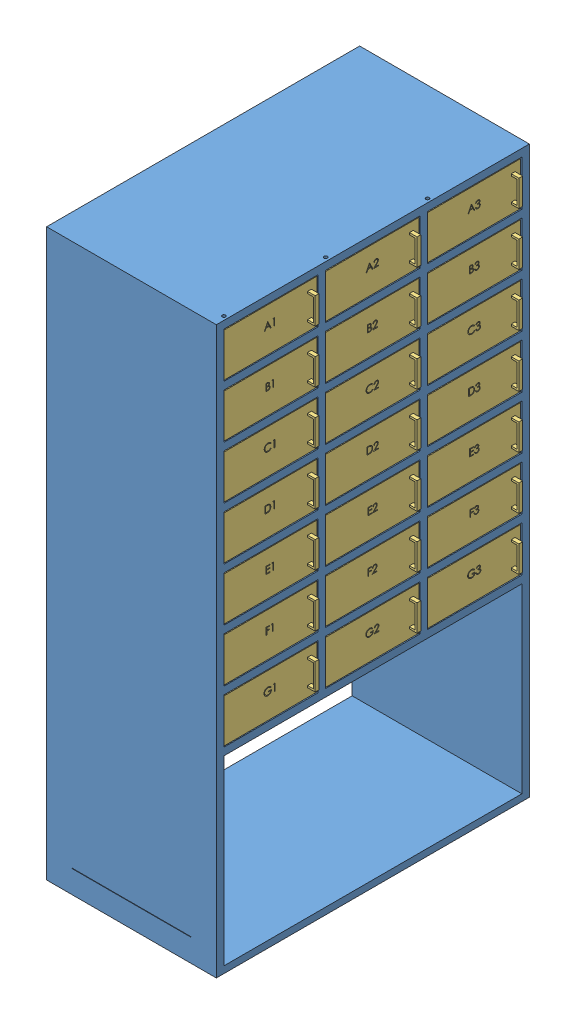
SolidWorks assembly new final assembly, configuration Default. Lengths in mm.
Overall size (470.03 1500 830).
64 component instances, 3 part files, 7 mates.
Components (placement in the parent):
- storage_frame-1: storage_frame [Default] at (-177.8301 428.9842 1746.1923) x (0 0 -1) z (1 0 0) size (830 1500 450)
- pivot mentese-1: pivot mentese [Varsayılan] at (37.1699 1388.9842 1996.1923) size (13 32 13)
- pivot mentese-2: pivot mentese [Varsayılan] at (37.1699 1308.9842 1996.1923) x (-0.999929 0 -0.011876) z (-0.011876 0 0.999929) size (13 32 13)
- door-3: door [Default] at (26.8762 1348.9842 1882.4685) x (0.999997 0 -0.002582) z (0.002582 0 0.999997) size (40 115 247.5)
- pivot mentese-3: pivot mentese [Varsayılan] at (37.1699 1248.9842 1996.1923) size (13 32 13)
- pivot mentese-4: pivot mentese [Varsayılan] at (37.1699 1108.9842 1996.1923) size (13 32 13)
- pivot mentese-5: pivot mentese [Varsayılan] at (37.1699 968.9842 1996.1923) size (13 32 13)
- pivot mentese-6: pivot mentese [Varsayılan] at (37.1699 828.9842 1996.1923) size (13 32 13)
- pivot mentese-7: pivot mentese [Varsayılan] at (37.1699 688.9842 1996.1923) size (13 32 13)
- pivot mentese-8: pivot mentese [Varsayılan] at (37.1699 548.9842 1996.1923) size (13 32 13)
- pivot mentese-9: pivot mentese [Varsayılan] at (37.1699 1168.9842 1996.1923) x (-0.999929 0 -0.011876) z (-0.011876 0 0.999929) size (13 32 13)
- pivot mentese-10: pivot mentese [Varsayılan] at (37.1699 1028.9842 1996.1923) x (-0.999929 0 -0.011876) z (-0.011876 0 0.999929) size (13 32 13)
- pivot mentese-11: pivot mentese [Varsayılan] at (37.1699 888.9842 1996.1923) x (-0.999929 0 -0.011876) z (-0.011876 0 0.999929) size (13 32 13)
- pivot mentese-12: pivot mentese [Varsayılan] at (37.1699 748.9842 1996.1923) x (-0.999929 0 -0.011876) z (-0.011876 0 0.999929) size (13 32 13)
- pivot mentese-13: pivot mentese [Varsayılan] at (37.1699 608.9842 1996.1923) x (-0.999929 0 -0.011876) z (-0.011876 0 0.999929) size (13 32 13)
- pivot mentese-14: pivot mentese [Varsayılan] at (37.1699 468.9842 1996.1923) x (-0.999929 0 -0.011876) z (-0.011876 0 0.999929) size (13 32 13)
- door-4: door [Default] at (26.8762 1208.9842 1882.4685) x (0.999997 0 -0.002582) z (0.002582 0 0.999997) size (40 115 247.5)
- door-5: door [Default] at (26.8762 1068.9842 1882.4685) x (0.999997 0 -0.002582) z (0.002582 0 0.999997) size (40 115 247.5)
- door-6: door [Default] at (26.8762 928.9842 1882.4685) x (0.999997 0 -0.002582) z (0.002582 0 0.999997) size (40 115 247.5)
- door-7: door [Default] at (26.8762 788.9842 1882.4685) x (0.999997 0 -0.002582) z (0.002582 0 0.999997) size (40 115 247.5)
- door-8: door [Default] at (26.8762 648.9842 1882.4685) x (0.999997 0 -0.002582) z (0.002582 0 0.999997) size (40 115 247.5)
- door-9: door [Default] at (26.8762 508.9842 1882.4685) x (0.999997 0 -0.002582) z (0.002582 0 0.999997) size (40 115 247.5)
- pivot mentese-15: pivot mentese [Varsayılan] at (37.1699 1388.9842 1726.1923) size (13 32 13)
- pivot mentese-16: pivot mentese [Varsayılan] at (37.1699 1388.9842 1456.1923) size (13 32 13)
- pivot mentese-17: pivot mentese [Varsayılan] at (37.1699 1308.9842 1726.1923) x (-0.999929 0 -0.011876) z (-0.011876 0 0.999929) size (13 32 13)
- pivot mentese-18: pivot mentese [Varsayılan] at (37.1699 1308.9842 1456.1923) x (-0.999929 0 -0.011876) z (-0.011876 0 0.999929) size (13 32 13)
- door-10: door [Default] at (26.8762 1348.9842 1612.4685) x (0.999997 0 -0.002582) z (0.002582 0 0.999997) size (40 115 247.5)
- door-11: door [Default] at (26.8762 1348.9842 1342.4685) x (0.999997 0 -0.002582) z (0.002582 0 0.999997) size (40 115 247.5)
- pivot mentese-19: pivot mentese [Varsayılan] at (37.1699 1248.9842 1726.1923) size (13 32 13)
- pivot mentese-20: pivot mentese [Varsayılan] at (37.1699 1248.9842 1456.1923) size (13 32 13)
- pivot mentese-21: pivot mentese [Varsayılan] at (37.1699 1108.9842 1726.1923) size (13 32 13)
- pivot mentese-22: pivot mentese [Varsayılan] at (37.1699 1108.9842 1456.1923) size (13 32 13)
- pivot mentese-23: pivot mentese [Varsayılan] at (37.1699 968.9842 1726.1923) size (13 32 13)
- pivot mentese-24: pivot mentese [Varsayılan] at (37.1699 968.9842 1456.1923) size (13 32 13)
- pivot mentese-25: pivot mentese [Varsayılan] at (37.1699 828.9842 1726.1923) size (13 32 13)
- pivot mentese-26: pivot mentese [Varsayılan] at (37.1699 828.9842 1456.1923) size (13 32 13)
- pivot mentese-27: pivot mentese [Varsayılan] at (37.1699 688.9842 1726.1923) size (13 32 13)
- pivot mentese-28: pivot mentese [Varsayılan] at (37.1699 688.9842 1456.1923) size (13 32 13)
- pivot mentese-29: pivot mentese [Varsayılan] at (37.1699 548.9842 1726.1923) size (13 32 13)
- pivot mentese-30: pivot mentese [Varsayılan] at (37.1699 548.9842 1456.1923) size (13 32 13)
- pivot mentese-31: pivot mentese [Varsayılan] at (37.1699 1168.9842 1726.1923) x (-0.999929 0 -0.011876) z (-0.011876 0 0.999929) size (13 32 13)
- pivot mentese-32: pivot mentese [Varsayılan] at (37.1699 1168.9842 1456.1923) x (-0.999929 0 -0.011876) z (-0.011876 0 0.999929) size (13 32 13)
- pivot mentese-33: pivot mentese [Varsayılan] at (37.1699 1028.9842 1726.1923) x (-0.999929 0 -0.011876) z (-0.011876 0 0.999929) size (13 32 13)
- pivot mentese-34: pivot mentese [Varsayılan] at (37.1699 1028.9842 1456.1923) x (-0.999929 0 -0.011876) z (-0.011876 0 0.999929) size (13 32 13)
- pivot mentese-35: pivot mentese [Varsayılan] at (37.1699 888.9842 1726.1923) x (-0.999929 0 -0.011876) z (-0.011876 0 0.999929) size (13 32 13)
- pivot mentese-36: pivot mentese [Varsayılan] at (37.1699 888.9842 1456.1923) x (-0.999929 0 -0.011876) z (-0.011876 0 0.999929) size (13 32 13)
- pivot mentese-37: pivot mentese [Varsayılan] at (37.1699 748.9842 1726.1923) x (-0.999929 0 -0.011876) z (-0.011876 0 0.999929) size (13 32 13)
- pivot mentese-38: pivot mentese [Varsayılan] at (37.1699 748.9842 1456.1923) x (-0.999929 0 -0.011876) z (-0.011876 0 0.999929) size (13 32 13)
- pivot mentese-39: pivot mentese [Varsayılan] at (37.1699 608.9842 1726.1923) x (-0.999929 0 -0.011876) z (-0.011876 0 0.999929) size (13 32 13)
- pivot mentese-40: pivot mentese [Varsayılan] at (37.1699 608.9842 1456.1923) x (-0.999929 0 -0.011876) z (-0.011876 0 0.999929) size (13 32 13)
- pivot mentese-41: pivot mentese [Varsayılan] at (37.1699 468.9842 1726.1923) x (-0.999929 0 -0.011876) z (-0.011876 0 0.999929) size (13 32 13)
- pivot mentese-42: pivot mentese [Varsayılan] at (37.1699 468.9842 1456.1923) x (-0.999929 0 -0.011876) z (-0.011876 0 0.999929) size (13 32 13)
- door-12: door [Default] at (26.8762 1208.9842 1612.4685) x (0.999997 0 -0.002582) z (0.002582 0 0.999997) size (40 115 247.5)
- door-13: door [Default] at (26.8762 1208.9842 1342.4685) x (0.999997 0 -0.002582) z (0.002582 0 0.999997) size (40 115 247.5)
- door-14: door [Default] at (26.8762 1068.9842 1612.4685) x (0.999997 0 -0.002582) z (0.002582 0 0.999997) size (40 115 247.5)
- door-15: door [Default] at (26.8762 1068.9842 1342.4685) x (0.999997 0 -0.002582) z (0.002582 0 0.999997) size (40 115 247.5)
- door-16: door [Default] at (26.8762 928.9842 1612.4685) x (0.999997 0 -0.002582) z (0.002582 0 0.999997) size (40 115 247.5)
- door-17: door [Default] at (26.8762 928.9842 1342.4685) x (0.999997 0 -0.002582) z (0.002582 0 0.999997) size (40 115 247.5)
- door-18: door [Default] at (26.8762 788.9842 1612.4685) x (0.999997 0 -0.002582) z (0.002582 0 0.999997) size (40 115 247.5)
- door-19: door [Default] at (26.8762 788.9842 1342.4685) x (0.999997 0 -0.002582) z (0.002582 0 0.999997) size (40 115 247.5)
- door-20: door [Default] at (26.8762 648.9842 1612.4685) x (0.999997 0 -0.002582) z (0.002582 0 0.999997) size (40 115 247.5)
- door-21: door [Default] at (26.8762 648.9842 1342.4685) x (0.999997 0 -0.002582) z (0.002582 0 0.999997) size (40 115 247.5)
- door-22: door [Default] at (26.8762 508.9842 1612.4685) x (0.999997 0 -0.002582) z (0.002582 0 0.999997) size (40 115 247.5)
- door-23: door [Default] at (26.8762 508.9842 1342.4685) x (0.999997 0 -0.002582) z (0.002582 0 0.999997) size (40 115 247.5)
Mates (geometry in assembly coordinates):
- Concentric10: concentric aligned: cylinder of storage_frame-1 through (37.1699 1441.4293 1996.1923) axis (0 -1 0) radius 4.4; cylinder of pivot mentese-1 through (37.1699 1416.9842 1996.1923) axis (0 -1 0) radius 3
- Coincident8: coincident anti-aligned: plane of storage_frame-1 through (-177.8301 1408.9842 1746.1923) normal (0 -1 0); plane of pivot mentese-1 through (30.6699 1408.9842 1996.1923) normal (0 1 0)
- Concentric11: concentric anti-aligned: cylinder of storage_frame-1 through (37.1699 1441.4293 1996.1923) axis (0 -1 0) radius 4.4; cylinder of pivot mentese-2 through (37.1699 1280.9842 1996.1923) axis (0 1 0) radius 3
- Coincident9: coincident anti-aligned: plane of storage_frame-1 through (-177.8301 1288.9842 1746.1923) normal (0 1 0); circle of pivot mentese-2
- Concentric12: concentric aligned: cylinder of pivot mentese-1 through (37.1699 1408.9842 1996.1923) axis (0 1 0) radius 4.4; cylinder of door-3 through (37.1699 1388.9842 1996.1923) axis (0 1 0) radius 4.4
- Concentric13: concentric aligned: cylinder of pivot mentese-2 through (37.1699 1288.9842 1996.1923) axis (0 -1 0) radius 4.4; cylinder of door-3 through (37.1699 1308.9842 1996.1923) axis (0 -1 0) radius 4.4
- Coincident10: coincident anti-aligned: plane of pivot mentese-2 through (41.8196 1291.4842 1996.2476) normal (0 1 0); plane of door-3 through (47.1957 1291.4842 2006.1665) normal (0 -1 0)
